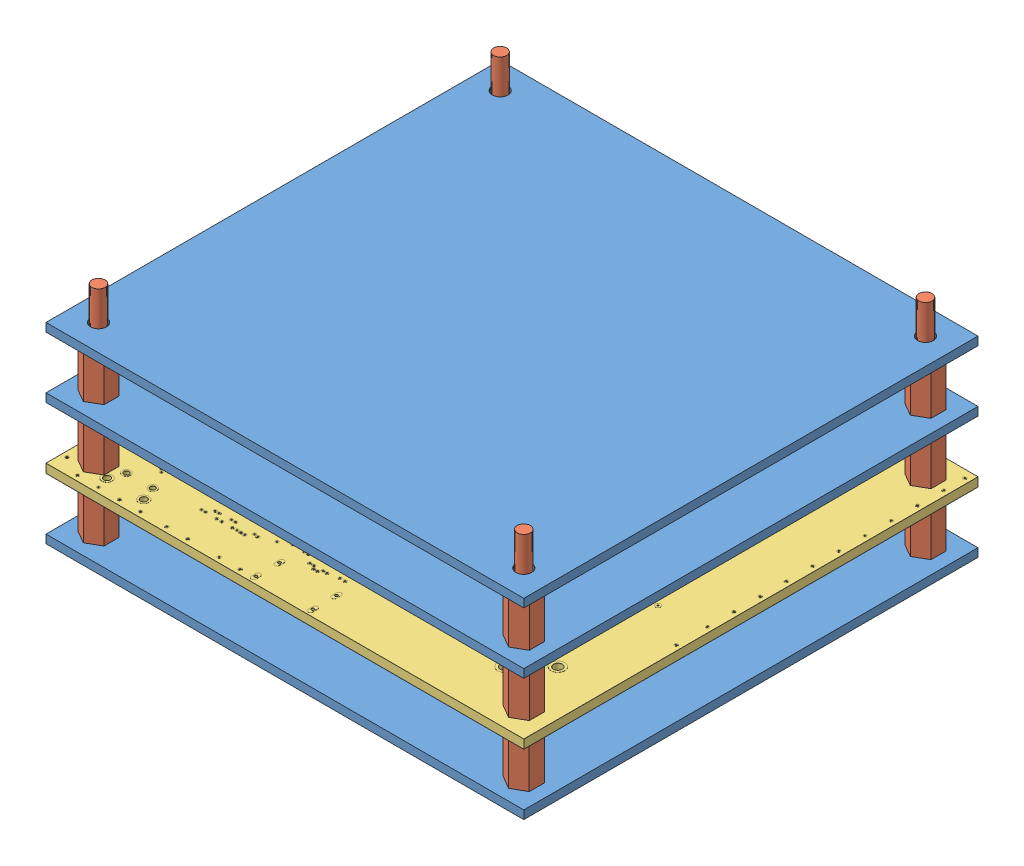
SolidWorks assembly STANDOFF_CONFIG, configuration Default. Lengths in mm.
Overall size (91 42.91 86.5).
16 component instances, 3 part files, 51 mates.
Components (placement in the parent):
- FAKE_PCB_2-1: FAKE_PCB_2 [Default] at (-10.3243 45.2469 113.4425) size (91 1.6 86.5)
- HEXAGONAL_STANDOFF-1: HEXAGONAL_STANDOFF [Default] at (-5.3243 46.8469 108.4425) size (5 18 5.77)
- HEXAGONAL_STANDOFF-2: HEXAGONAL_STANDOFF [Default] at (75.6757 46.8469 108.4425) x (0.999954 0 0.00961) z (-0.00961 0 0.999954) size (5 18 5.77)
- HEXAGONAL_STANDOFF-3: HEXAGONAL_STANDOFF [Default] at (75.6757 46.8469 31.9425) size (5 18 5.77)
- HEXAGONAL_STANDOFF-4: HEXAGONAL_STANDOFF [Default] at (-5.3243 46.8469 31.9425) x (0.996821 0 0.079672) z (-0.079672 0 0.996821) size (5 18 5.77)
- FLIGHT_COMPUTER_PCB4_2-1: FLIGHT_COMPUTER_PCB4_2 [Default] at (-10.3243 58.5003 113.4425) x (0 0 -1) z (0 -1 0) size (86.5 91 1.74)
- HEXAGONAL_STANDOFF-10: HEXAGONAL_STANDOFF [Default] at (-5.3243 58.5536 108.4425) size (5 18 5.77)
- HEXAGONAL_STANDOFF-11: HEXAGONAL_STANDOFF [Default] at (75.6757 58.5536 108.4425) size (5 18 5.77)
- HEXAGONAL_STANDOFF-12: HEXAGONAL_STANDOFF [Default] at (75.6757 58.5536 31.9425) size (5 18 5.77)
- HEXAGONAL_STANDOFF-13: HEXAGONAL_STANDOFF [Default] at (-5.3243 58.5536 31.9425) size (5 18 5.77)
- FAKE_PCB_2-2: FAKE_PCB_2 [Default] at (-10.3243 68.5536 113.4425) size (91 1.6 86.5)
- HEXAGONAL_STANDOFF-14: HEXAGONAL_STANDOFF [Default] at (-5.3243 70.1536 108.4425) size (5 18 5.77)
- HEXAGONAL_STANDOFF-15: HEXAGONAL_STANDOFF [Default] at (-5.3243 70.1536 31.9425) size (5 18 5.77)
- HEXAGONAL_STANDOFF-16: HEXAGONAL_STANDOFF [Default] at (75.6757 70.1536 31.9425) size (5 18 5.77)
- HEXAGONAL_STANDOFF-17: HEXAGONAL_STANDOFF [Default] at (75.6757 70.1536 108.4425) size (5 18 5.77)
- FAKE_PCB_2-3: FAKE_PCB_2 [Default] at (-10.3243 80.1536 113.4425) size (91 1.6 86.5)
Mates (geometry in assembly coordinates):
- Coincident1: coincident anti-aligned: plane of FAKE_PCB_2-1 through (-10.3243 46.8469 113.4425) normal (0 1 0); plane of HEXAGONAL_STANDOFF-1 through (-5.3243 46.8469 108.4425) normal (0 -1 0)
- Concentric1: concentric anti-aligned: circle of FAKE_PCB_2-1; circle of HEXAGONAL_STANDOFF-1
- Coincident2: coincident anti-aligned: plane of FAKE_PCB_2-1 through (-10.3243 46.8469 113.4425) normal (0 1 0); plane of HEXAGONAL_STANDOFF-2 through (75.6757 46.8469 108.4425) normal (0 -1 0)
- Concentric2: concentric anti-aligned: circle of FAKE_PCB_2-1; circle of HEXAGONAL_STANDOFF-2
- Coincident3: coincident anti-aligned: plane of FAKE_PCB_2-1 through (-10.3243 46.8469 113.4425) normal (0 1 0); plane of HEXAGONAL_STANDOFF-3 through (75.6757 46.8469 31.9425) normal (0 -1 0)
- Concentric3: concentric anti-aligned: circle of FAKE_PCB_2-1; circle of HEXAGONAL_STANDOFF-3
- Coincident4: coincident anti-aligned: plane of FAKE_PCB_2-1 through (-10.3243 46.8469 113.4425) normal (0 1 0); plane of HEXAGONAL_STANDOFF-4 through (-5.3243 46.8469 31.9425) normal (0 -1 0)
- Concentric4: concentric anti-aligned: circle of FAKE_PCB_2-1; circle of HEXAGONAL_STANDOFF-4
- Coincident5: coincident anti-aligned: plane of HEXAGONAL_STANDOFF-3 through (75.6757 56.8469 31.9425) normal (0 1 0); plane of FAKE_PCB_2-2 through (-10.3243 56.8469 113.4425) normal (0 -1 0)
- Coincident6: coincident anti-aligned: plane of HEXAGONAL_STANDOFF-2 through (75.6757 56.8469 108.4425) normal (0 1 0); plane of FAKE_PCB_2-2 through (-10.3243 56.8469 113.4425) normal (0 -1 0)
- Coincident7: coincident anti-aligned: plane of HEXAGONAL_STANDOFF-4 through (-5.3243 56.8469 31.9425) normal (0 1 0); plane of FAKE_PCB_2-2 through (-10.3243 56.8469 113.4425) normal (0 -1 0)
- Concentric6: concentric anti-aligned: cylinder of HEXAGONAL_STANDOFF-3 through (75.6757 64.8469 31.9425) axis (0 -1 0) radius 1.25; circle of FAKE_PCB_2-2
- Concentric7: concentric anti-aligned: cylinder of HEXAGONAL_STANDOFF-4 through (-5.3243 64.8469 31.9425) axis (0 -1 0) radius 1.25; cylinder of FAKE_PCB_2-2 through (-5.3243 48.4469 31.9425) axis (0 1 0) radius 1.5
- Concentric8: concentric anti-aligned: cylinder of HEXAGONAL_STANDOFF-1 through (-5.3243 64.8469 108.4425) axis (0 -1 0) radius 1.25; cylinder of FAKE_PCB_2-2 through (-5.3243 48.4469 108.4425) axis (0 1 0) radius 1.5
- Concentric9: concentric anti-aligned: cylinder of HEXAGONAL_STANDOFF-2 through (75.6757 64.8469 108.4425) axis (0 -1 0) radius 1.25; cylinder of FAKE_PCB_2-2 through (75.6757 48.4469 108.4425) axis (0 1 0) radius 1.5
- Concentric10: concentric aligned: cylinder of HEXAGONAL_STANDOFF-1 through (-5.3243 64.8469 108.4425) axis (0 -1 0) radius 1.25; cylinder of HEXAGONAL_STANDOFF-5 through (-5.3243 66.4469 108.4425) axis (0 -1 0) radius 1.25
- Coincident8: coincident anti-aligned: plane of FAKE_PCB_2-2 through (-10.3243 58.4469 113.4425) normal (0 1 0); plane of HEXAGONAL_STANDOFF-5 through (-5.3243 58.4469 108.4425) normal (0 -1 0)
- Concentric11: concentric aligned: cylinder of HEXAGONAL_STANDOFF-2 through (75.6757 64.8469 108.4425) axis (0 -1 0) radius 1.25; cylinder of HEXAGONAL_STANDOFF-6 through (75.6757 66.4469 108.4425) axis (0 -1 0) radius 1.25
- Coincident9: coincident anti-aligned: plane of FAKE_PCB_2-2 through (-10.3243 58.4469 113.4425) normal (0 1 0); plane of HEXAGONAL_STANDOFF-6 through (75.6757 58.4469 108.4425) normal (0 -1 0)
- Concentric12: concentric aligned: cylinder of HEXAGONAL_STANDOFF-3 through (75.6757 64.8469 31.9425) axis (0 -1 0) radius 1.25; cylinder of HEXAGONAL_STANDOFF-8 through (75.6757 66.4469 31.9425) axis (0 -1 0) radius 1.25
- Coincident10: coincident anti-aligned: plane of FAKE_PCB_2-2 through (-10.3243 58.4469 113.4425) normal (0 1 0); plane of HEXAGONAL_STANDOFF-8 through (75.6757 58.4469 31.9425) normal (0 -1 0)
- Concentric13: concentric aligned: cylinder of HEXAGONAL_STANDOFF-4 through (-5.3243 64.8469 31.9425) axis (0 -1 0) radius 1.25; cylinder of HEXAGONAL_STANDOFF-7 through (-5.3243 66.4469 31.9425) axis (0 -1 0) radius 1.25
- Coincident11: coincident anti-aligned: plane of FAKE_PCB_2-2 through (-10.3243 58.4469 113.4425) normal (0 1 0); plane of HEXAGONAL_STANDOFF-7 through (-5.3243 58.4469 31.9425) normal (0 -1 0)
- Concentric14: concentric anti-aligned: cylinder of HEXAGONAL_STANDOFF-8 through (75.6757 76.4469 31.9425) axis (0 -1 0) radius 1.25; cylinder of FAKE_PCB_2-3 through (75.6757 60.0469 31.9425) axis (0 1 0) radius 1.5
- Concentric15: concentric anti-aligned: cylinder of HEXAGONAL_STANDOFF-5 through (-5.3243 76.4469 108.4425) axis (0 -1 0) radius 1.25; cylinder of FAKE_PCB_2-3 through (-5.3243 60.0469 108.4425) axis (0 1 0) radius 1.5
- Coincident12: coincident anti-aligned: plane of HEXAGONAL_STANDOFF-8 through (75.6757 68.4469 31.9425) normal (0 1 0); plane of FAKE_PCB_2-3 through (-10.3243 68.4469 113.4425) normal (0 -1 0)
- Concentric16: concentric anti-aligned: cylinder of HEXAGONAL_STANDOFF-4 through (-5.3243 64.8469 31.9425) axis (0 -1 0) radius 1.25; cylinder of FLIGHT_COMPUTER_PCB4_2-1 through (-5.3243 48.5536 31.9425) axis (0 1 0) radius 1.5
- Concentric17: concentric anti-aligned: cylinder of HEXAGONAL_STANDOFF-2 through (75.6757 64.8469 108.4425) axis (0 -1 0) radius 1.25; cylinder of FLIGHT_COMPUTER_PCB4_2-1 through (75.6757 48.5536 108.4425) axis (0 1 0) radius 1.5
- Coincident13: coincident anti-aligned: plane of HEXAGONAL_STANDOFF-2 through (75.6757 56.8469 108.4425) normal (0 1 0); plane of FLIGHT_COMPUTER_PCB4_2-1 through (35.1757 56.8469 70.1925) normal (0 -1 0)
- Concentric18: concentric aligned: cylinder of HEXAGONAL_STANDOFF-2 through (75.6757 64.8469 108.4425) axis (0 -1 0) radius 1.25; cylinder of HEXAGONAL_STANDOFF-11 through (75.6757 66.5536 108.4425) axis (0 -1 0) radius 1.25
- Coincident14: coincident anti-aligned: plane of FLIGHT_COMPUTER_PCB4_2-1 through (35.1757 58.5536 70.1925) normal (0 1 0); plane of HEXAGONAL_STANDOFF-11 through (75.6757 58.5536 108.4425) normal (0 -1 0)
- Concentric19: concentric aligned: cylinder of HEXAGONAL_STANDOFF-1 through (-5.3243 64.8469 108.4425) axis (0 -1 0) radius 1.25; cylinder of HEXAGONAL_STANDOFF-10 through (-5.3243 66.5536 108.4425) axis (0 -1 0) radius 1.25
- Coincident15: coincident anti-aligned: plane of FLIGHT_COMPUTER_PCB4_2-1 through (35.1757 58.5536 70.1925) normal (0 1 0); plane of HEXAGONAL_STANDOFF-10 through (-5.3243 58.5536 108.4425) normal (0 -1 0)
- Concentric20: concentric aligned: cylinder of HEXAGONAL_STANDOFF-3 through (75.6757 64.8469 31.9425) axis (0 -1 0) radius 1.25; cylinder of HEXAGONAL_STANDOFF-12 through (75.6757 66.5536 31.9425) axis (0 -1 0) radius 1.25
- Coincident16: coincident anti-aligned: plane of FLIGHT_COMPUTER_PCB4_2-1 through (35.1757 58.5536 70.1925) normal (0 1 0); plane of HEXAGONAL_STANDOFF-12 through (75.6757 58.5536 31.9425) normal (0 -1 0)
- Concentric21: concentric aligned: cylinder of HEXAGONAL_STANDOFF-4 through (-5.3243 64.8469 31.9425) axis (0 -1 0) radius 1.25; cylinder of HEXAGONAL_STANDOFF-13 through (-5.3243 66.5536 31.9425) axis (0 -1 0) radius 1.25
- Coincident17: coincident anti-aligned: plane of FLIGHT_COMPUTER_PCB4_2-1 through (35.1757 58.5536 70.1925) normal (0 1 0); plane of HEXAGONAL_STANDOFF-13 through (-5.3243 58.5536 31.9425) normal (0 -1 0)
- Concentric22: concentric anti-aligned: cylinder of HEXAGONAL_STANDOFF-10 through (-5.3243 76.5536 108.4425) axis (0 -1 0) radius 1.25; cylinder of FAKE_PCB_2-2 through (-5.3243 60.1536 108.4425) axis (0 1 0) radius 1.5
- Concentric23: concentric anti-aligned: cylinder of HEXAGONAL_STANDOFF-12 through (75.6757 76.5536 31.9425) axis (0 -1 0) radius 1.25; cylinder of FAKE_PCB_2-2 through (75.6757 60.1536 31.9425) axis (0 1 0) radius 1.5
- Coincident18: coincident anti-aligned: plane of HEXAGONAL_STANDOFF-11 through (75.6757 68.5536 108.4425) normal (0 1 0); plane of FAKE_PCB_2-2 through (-10.3243 68.5536 113.4425) normal (0 -1 0)
- Concentric24: concentric aligned: cylinder of HEXAGONAL_STANDOFF-10 through (-5.3243 76.5536 108.4425) axis (0 -1 0) radius 1.25; cylinder of HEXAGONAL_STANDOFF-14 through (-5.3243 78.1536 108.4425) axis (0 -1 0) radius 1.25
- Coincident19: coincident anti-aligned: plane of FAKE_PCB_2-2 through (-10.3243 70.1536 113.4425) normal (0 1 0); plane of HEXAGONAL_STANDOFF-14 through (-5.3243 70.1536 108.4425) normal (0 -1 0)
- Concentric25: concentric aligned: cylinder of HEXAGONAL_STANDOFF-13 through (-5.3243 76.5536 31.9425) axis (0 -1 0) radius 1.25; cylinder of HEXAGONAL_STANDOFF-15 through (-5.3243 78.1536 31.9425) axis (0 -1 0) radius 1.25
- Coincident20: coincident anti-aligned: plane of FAKE_PCB_2-2 through (-10.3243 70.1536 113.4425) normal (0 1 0); plane of HEXAGONAL_STANDOFF-15 through (-5.3243 70.1536 31.9425) normal (0 -1 0)
- Concentric26: concentric aligned: cylinder of HEXAGONAL_STANDOFF-12 through (75.6757 76.5536 31.9425) axis (0 -1 0) radius 1.25; cylinder of HEXAGONAL_STANDOFF-16 through (75.6757 78.1536 31.9425) axis (0 -1 0) radius 1.25
- Coincident21: coincident anti-aligned: plane of FAKE_PCB_2-2 through (-10.3243 70.1536 113.4425) normal (0 1 0); plane of HEXAGONAL_STANDOFF-16 through (75.6757 70.1536 31.9425) normal (0 -1 0)
- Concentric27: concentric aligned: cylinder of HEXAGONAL_STANDOFF-11 through (75.6757 76.5536 108.4425) axis (0 -1 0) radius 1.25; circle of HEXAGONAL_STANDOFF-17
- Coincident23: coincident anti-aligned: plane of FAKE_PCB_2-2 through (-10.3243 70.1536 113.4425) normal (0 1 0); plane of HEXAGONAL_STANDOFF-17 through (75.6757 70.1536 108.4425) normal (0 -1 0)
- Concentric28: concentric anti-aligned: cylinder of HEXAGONAL_STANDOFF-17 through (75.6757 88.1536 108.4425) axis (0 -1 0) radius 1.25; cylinder of FAKE_PCB_2-3 through (75.6757 71.7536 108.4425) axis (0 1 0) radius 1.5
- Concentric29: concentric anti-aligned: cylinder of HEXAGONAL_STANDOFF-15 through (-5.3243 88.1536 31.9425) axis (0 -1 0) radius 1.25; cylinder of FAKE_PCB_2-3 through (-5.3243 71.7536 31.9425) axis (0 1 0) radius 1.5
- Coincident24: coincident anti-aligned: plane of HEXAGONAL_STANDOFF-16 through (75.6757 80.1536 31.9425) normal (0 1 0); plane of FAKE_PCB_2-3 through (-10.3243 80.1536 113.4425) normal (0 -1 0)
